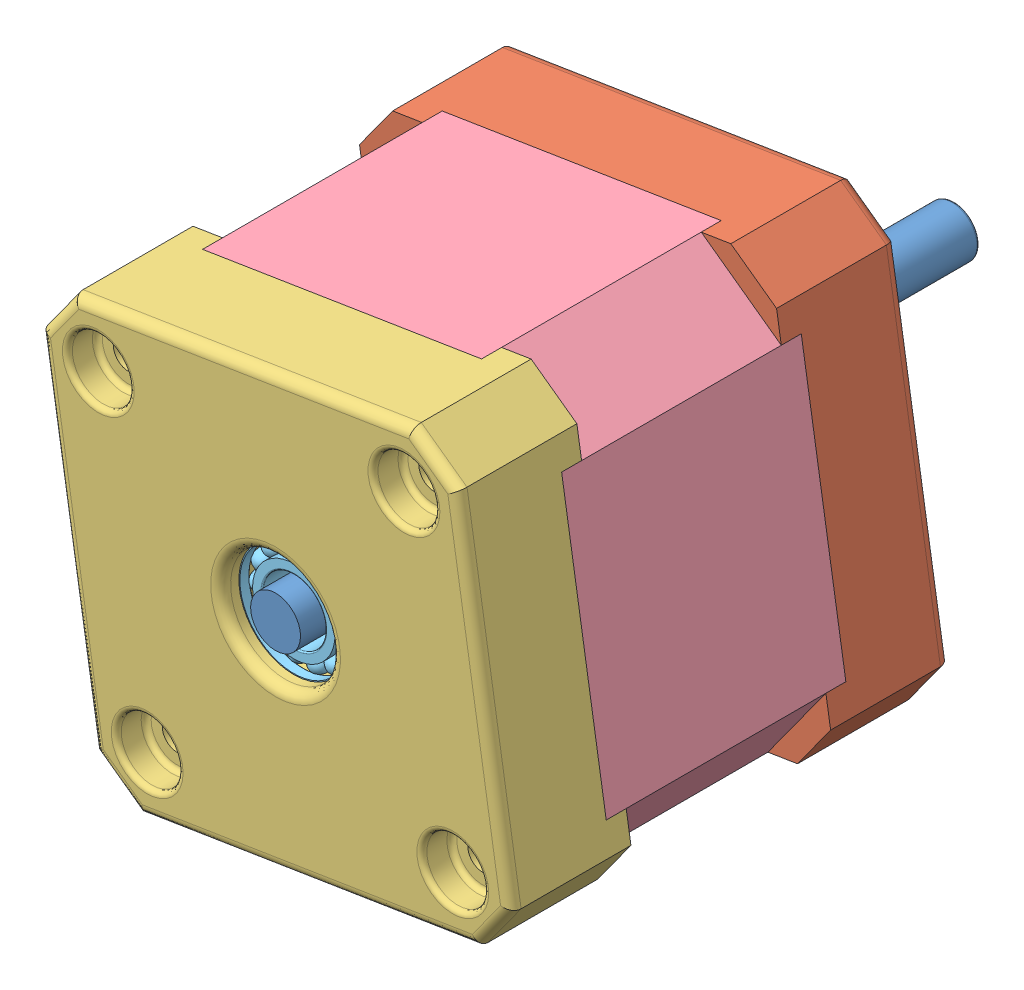
SolidWorks assembly EI_Nema17, configuration Default. Lengths in mm.
Overall size (48.45 48.45 68).
7 component instances, 6 part files, 14 mates.
Components (placement in the parent):
- Axial rod 1-1: Axial rod 1 [Default] at (-58.2353 9.2851 111.3831) x (0.407635 0.913145 0) z (0 0 -1) size (5 5 68)
- Back plate 1-1: Back plate 1 [Default] at (-58.2353 9.2851 67.3831) x (-0.157849 0.987463 0) z (0 0 1) size (42.3 42.3 14)
- Base 1-1: Base 1 [Default] at (-58.2353 9.2851 111.3831) x (-0.157849 0.987463 0) z (0 0 -1) size (42.3 42.3 12)
- Body 1-1: Body 1 [Default] at (-58.2353 9.2851 77.3831) x (-0.157849 0.987463 0) z (0 0 1) size (42.3 42.3 24)
- Pulley 1-1: Pulley 1 [Default] at (-58.2353 9.2851 59.7552) x (0 0 -1) z (-0.01367 0.999907 0) (suppressed, hidden)
- instrument ball bearing_68_am-1: instrument ball bearing_68_am [PreviewCfg] at (-58.2353 9.2851 107.9706) x (0 0 -1) z (1 0 0) size (3.17 12.7 12.7)
- instrument ball bearing_68_am-2: instrument ball bearing_68_am [PreviewCfg] at (-58.2353 9.2851 70.7956) x (0 0 -1) z (1 0 0) size (3.17 12.7 12.7)
Mates (geometry in assembly coordinates):
- Coincident1: coincident anti-aligned: plane of Back plate 1-1 through (-58.2353 9.2851 77.3831) normal (0 0 1); plane of Body 1-1 through (-58.2353 9.2851 77.3831) normal (0 0 -1)
- Coincident2: coincident aligned: plane of Back plate 1-1 through (-76.4131 -10.9884 79.3831) normal (-0.987463 -0.157849 0); plane of Body 1-1 through (-76.8866 -8.026 101.3831) normal (-0.987463 -0.157849 0)
- Coincident3: coincident aligned: plane of Back plate 1-1 through (-37.9618 -8.8926 79.3831) normal (0.157849 -0.987463 0); plane of Body 1-1 through (-40.9242 -9.3662 101.3831) normal (0.157849 -0.987463 0)
- Coincident4: coincident aligned: plane of Base 1-1 through (-76.4131 -10.9884 99.3831) normal (-0.987463 -0.157849 0); plane of Body 1-1 through (-76.8866 -8.026 101.3831) normal (-0.987463 -0.157849 0)
- Coincident5: coincident anti-aligned: plane of Base 1-1 through (-58.2353 9.2851 101.3831) normal (0 0 -1); plane of Body 1-1 through (-58.2353 9.2851 101.3831) normal (0 0 1)
- Coincident6: coincident aligned: plane of Base 1-1 through (-71.8318 -14.3069 99.3831) normal (0.157849 -0.987463 0); plane of Body 1-1 through (-40.9242 -9.3662 101.3831) normal (0.157849 -0.987463 0)
- Concentric1: concentric anti-aligned: cylinder of Axial rod 1-1 through (-58.2353 9.2851 43.3831) axis (0 0 1) radius 2.5; cylinder of Back plate 1-1 through (-58.2353 9.2851 79.3831) axis (0 0 -1) radius 2.5
- Coincident7: coincident aligned: plane of Axial rod 1-1 through (-58.2353 9.2851 111.3831) normal (0 0 1); plane of Base 1-1 through (-58.2353 9.2851 111.3831) normal (0 0 1)
- Concentric2: concentric anti-aligned: cylinder of Axial rod 1-1 through (-58.2353 9.2851 43.3831) axis (0 0 1) radius 2.5; cylinder of Pulley 1-1 through (-58.2353 9.2851 59.7552) axis (0 0 -1) radius 2.5
- Concentric3: concentric anti-aligned: cylinder of Axial rod 1-1 through (-58.2353 9.2851 43.3831) axis (0 0 1) radius 2.5; cylinder of instrument ball bearing_68_am-2 through (-58.2353 9.2851 91.4331) axis (0 0 -1) radius 3.175
- Coincident8: coincident aligned: plane of Back plate 1-1 through (-58.2353 9.2851 72.3831) normal (0 0 -1); circle of instrument ball bearing_68_am-2
- Concentric4: concentric anti-aligned: cylinder of Axial rod 1-1 through (-58.2353 9.2851 43.3831) axis (0 0 1) radius 2.5; cylinder of instrument ball bearing_68_am-1 through (-58.2353 9.2851 128.6081) axis (0 0 -1) radius 3.175
- Coincident9: coincident anti-aligned: plane of Base 1-1 through (-58.2353 9.2851 106.3831) normal (0 0 1); circle of instrument ball bearing_68_am-1
- Lock1: lock: unknown of Axial rod 1-1; unknown of Pulley 1-1
